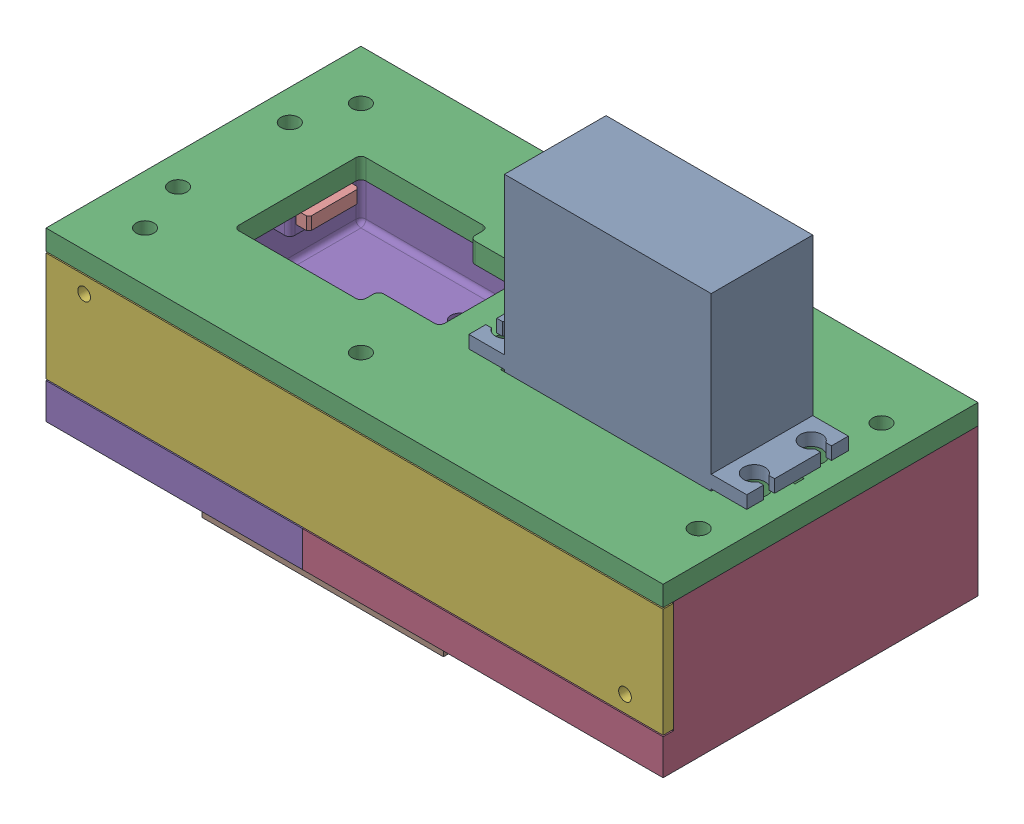
SolidWorks assembly Gearbox, configuration Default. Lengths in mm.
Overall size (121.5 71.3 62).
9 component instances, 8 part files, 22 mates.
Components (placement in the parent):
- Big Servo-1: Big Servo [Default] at (39.12 46.55 0) x (-1 0 0) z (0 1 0) size (54.7 20 45.2)
- 180gear-1: 180gear [Default] at (28.5 23.1 0) x (0 -1 0) z (-0.87579 0 0.482693) size (10 41.91 41.91)
- 360housing_top-1: 360housing_top [Default] at (0 29 0) size (121.5 4 62) (hidden)
- 360housing_bottom-1: 360housing_bottom [Default] at origin size (121.5 29 62)
- 360housing_cover-1: 360housing_cover [Default] at (10.25 18 29) size (121.5 21.5 2) (hidden)
- 360housing_support-1: 360housing_support [Default] at (0 -5 -20) size (47.5 5 6)
- 360housing_support-2: 360housing_support [Default] at (0 -5 24) size (47.5 5 6)
- testnut-1: testnut [Default] at (-44.5 21.0599 -11) x (-0.489767 0 0.871854) z (-0.871854 0 -0.489767) size (6.27 2.38 5.43)
- nutcover-1: nutcover [Default] at (-44.4325 21.2089 -11) size (10.25 2.5 10)
Mates (geometry in assembly coordinates):
- Concentric2: concentric anti-aligned: cylinder of Big Servo-1 through (28.5 21.1 0) axis (0 1 0) radius 3; cylinder of 180gear-1 through (28.5 11.1 0) axis (0 -1 0) radius 1.7
- Coincident3: coincident anti-aligned: plane of Big Servo-1 through (28.5 21.1 0) normal (0 -1 0); plane of 180gear-1 through (28.5 21.1 0) normal (0 1 0)
- Coincident4: coordinate: point of 360housing_bottom-1
- Coincident5: coincident anti-aligned: plane of 360housing_top-1 through (0 29 0) normal (0 -1 0); plane of 360housing_bottom-1 through (0 29 0) normal (0 1 0)
- Concentric3: concentric aligned: cylinder of 360housing_top-1 through (-44.5 29 -11) axis (0 1 0) radius 1.75; cylinder of 360housing_bottom-1 through (-44.5 14.0503 -11) axis (0 1 0) radius 1.75
- Concentric4: concentric aligned: cylinder of 360housing_top-1 through (-44.5 29 11) axis (0 1 0) radius 1.75; cylinder of 360housing_bottom-1 through (-44.5 14.0503 11) axis (0 1 0) radius 1.75
- Coincident6: coincident anti-aligned: plane of 360housing_bottom-1 through (0 0 0) normal (0 -1 0); plane of 360housing_support-1 through (0 0 -20) normal (0 1 0)
- Concentric5: concentric anti-aligned: cylinder of 360housing_bottom-1 through (20 0 -20) axis (0 1 0) radius 1.75; cylinder of 360housing_support-1 through (20 0 -20) axis (0 -1 0) radius 1.75
- Concentric6: concentric anti-aligned: cylinder of 360housing_bottom-1 through (-20 0 -20) axis (0 1 0) radius 1.75; cylinder of 360housing_support-1 through (-20 0 -20) axis (0 -1 0) radius 1.75
- Coincident7: coincident anti-aligned: plane of 360housing_bottom-1 through (0 0 0) normal (0 -1 0); plane of 360housing_support-2 through (0 0 24) normal (0 1 0)
- Concentric7: concentric anti-aligned: cylinder of 360housing_bottom-1 through (20 0 24) axis (0 1 0) radius 1.75; cylinder of 360housing_support-2 through (20 0 24) axis (0 -1 0) radius 1.75
- Concentric8: concentric anti-aligned: cylinder of 360housing_bottom-1 through (-20 0 24) axis (0 1 0) radius 1.75; cylinder of 360housing_support-2 through (-20 0 24) axis (0 -1 0) radius 1.75
- Coincident8: coincident anti-aligned: plane of 360housing_bottom-1 through (0 29 29) normal (0 0 1); plane of 360housing_cover-1 through (10.25 18 29) normal (0 0 -1)
- Concentric9: concentric aligned: cylinder of 360housing_bottom-1 through (-43 25.5 23.5) axis (0 0 1) radius 1.25; cylinder of 360housing_cover-1 through (-43 25.5 29) axis (0 0 1) radius 1.25
- Concentric10: concentric aligned: cylinder of 360housing_bottom-1 through (63.5 10.5 23.5) axis (0 0 1) radius 1.25; cylinder of 360housing_cover-1 through (63.5 10.5 29) axis (0 0 1) radius 1.25
- Coincident9: coincident anti-aligned: plane of Big Servo-1 through (11.77 33 10) normal (0 -1 0); plane of 360housing_top-1 through (0 33 0) normal (0 1 0)
- Concentric11: concentric anti-aligned: cylinder of Big Servo-1 through (14.68 66.3 -5.6) axis (0 -1 0) radius 2.1; cylinder of 360housing_top-1 through (14.68 29 -5.6) axis (0 1 0) radius 2.5
- Concentric12: concentric anti-aligned: cylinder of Big Servo-1 through (14.68 66.3 5.6) axis (0 -1 0) radius 2.1; cylinder of 360housing_top-1 through (14.68 29 5.6) axis (0 1 0) radius 2.5
- Concentric13: concentric anti-aligned: cylinder of 360housing_bottom-1 through (-44.5 14.0503 -11) axis (0 1 0) radius 1.75; cylinder of testnut-1 through (-44.5 23.4399 -11) axis (0 -1 0) radius 1.5
- Parallel1: parallel anti-aligned: plane of testnut-1; plane of nutcover-1 through (-42.2446 13.8554 -9.5925) normal (-0.866025 0 -0.5)
- Coincident10: coincident anti-aligned: plane of 360housing_bottom-1 through (-38.75 19 -16.75) normal (1 0 0); plane of nutcover-1 through (-38.75 23.7089 -11) normal (-1 0 0)
- Width1: width aligned: plane of 360housing_bottom-1 through (0 24 -14) normal (0 0 1); plane of nutcover-1 through (0 24 -8) normal (0 0 -1); plane of 360housing_bottom-1 through (-44.4325 23.7089 -8.05) normal (0 0 1); plane of nutcover-1 through (-44.4325 23.7089 -13.95) normal (0 0 -1)
